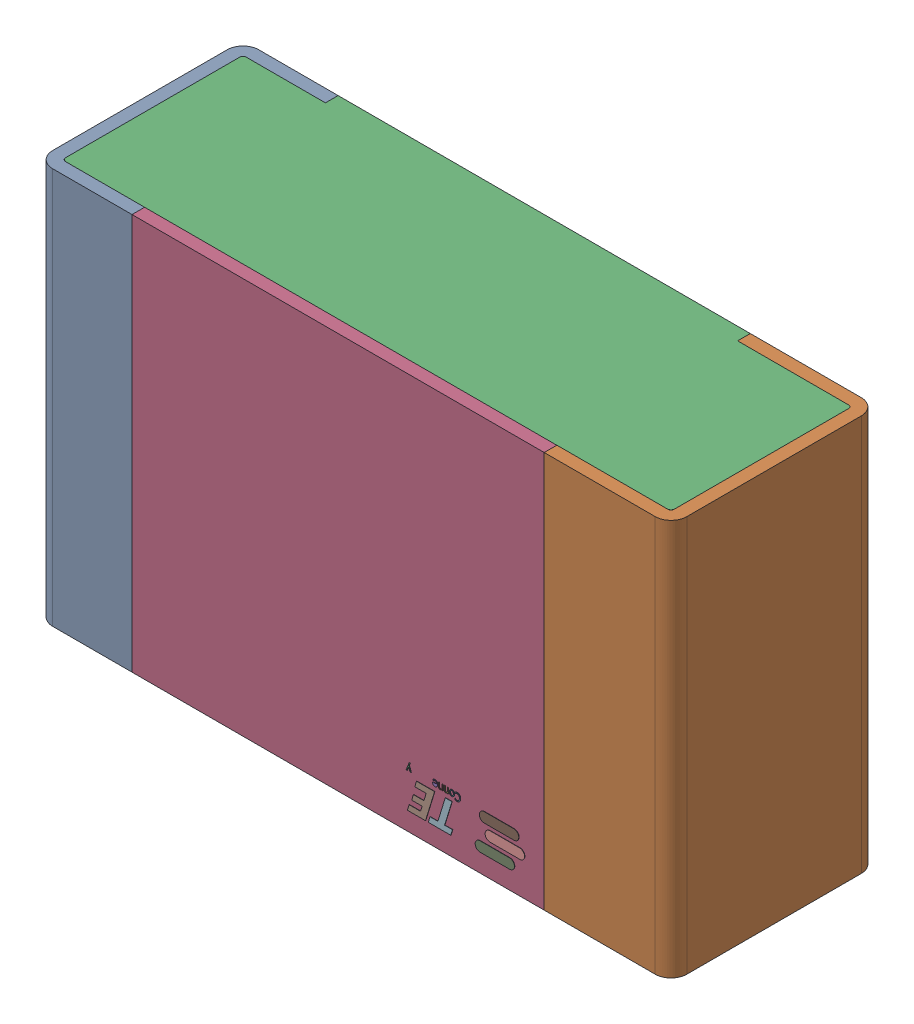
SolidWorks assembly R_MH3.step, configuration Default. Lengths in mm.
Overall size (2 1.25 0.65).
5 component instances, 4 part files, 0 mates.
Components (placement in the parent):
- Res_TE_Connectivity_CPF0805B66R5E1_eec.step-1: Res_TE_Connectivity_CPF0805B66R5E1_eec.step [Default] at (51.169 2.413 0) x (-1 0 0) z (0 0 1) size (2 1.25 0.65)
  - 1.step-1: 1.step [Default] at origin size (2 1.25 0.65)
  - 2.step-1: 2.step [Default] at origin size (1.92 1.25 0.61)
  - 3.step-1: 3.step [Default] at origin size (1.3 1.25 0.04)
  - TE connectivity Logo 1 (2).step-1: TE connectivity Logo 1 (2).step [Default] at (5.4285 0.313 0.551) x (-1 0 0) z (0 0 1) size (0.37 0.13 0.11)
